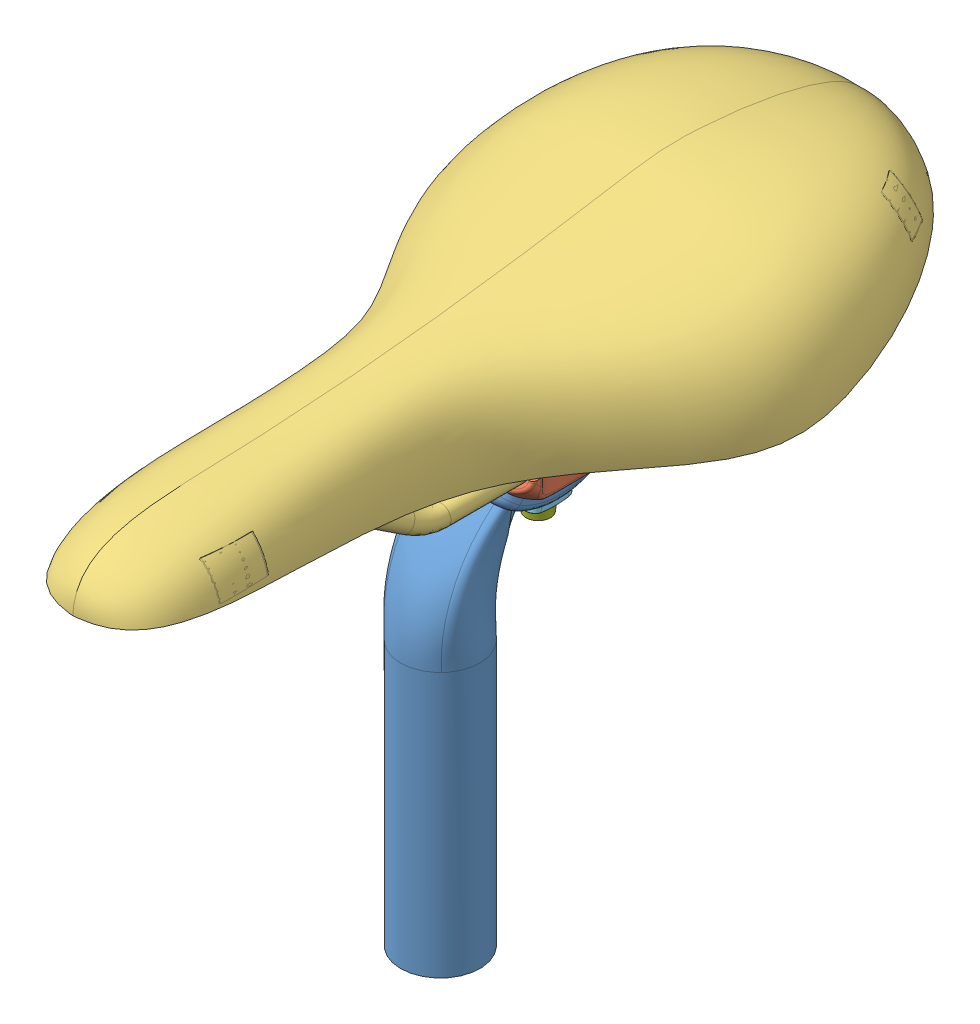
SolidWorks assembly seat_stand, configuration Default. Lengths in mm.
Overall size (140.06 222.45 302.54).
12 component instances, 8 part files, 30 mates.
Components (placement in the parent):
- stand-1: stand [Default] at (5.0908 187.7856 -27.9009) size (40.88 156.43 61.72)
- part_2-1: part_2 [Default] at (5.0908 219.2856 -27.9009) x (0 0 -1) z (1 0 0) size (41.9 15.12 55.13)
- seat_cover-1: seat_cover [Default] at (5.0908 217.7738 -164.6112) x (-1 0 0) z (0 0.049938 -0.998752) size (140.06 58.35 300)
- upper_part_3-1: upper_part_3 [Default] at (5.0908 211.7856 -27.9009) x (0 0 1) z (-1 0 0) size (39.3 9.87 55.04)
- hole_4part-1: hole_4part [Default] at (-6.9092 187.7856 -27.9009) size (12.84 3.36 16.77)
- hole_5part-1: hole_5part [Default] at (-6.9092 218.5862 -27.9009) x (1 0 0) z (0 0 -1) size (12.84 3.15 16.57)
- hole_5part-2: hole_5part [Default] at (17.0908 218.5862 -27.9009) x (1 0 0) z (0 0 -1) size (12.84 3.15 16.57)
- hole_4part-3: hole_4part [Default] at (17.0908 187.7856 -27.9009) size (12.84 3.36 16.77)
- hexalobular socket cheese head_iso-4: hexalobular socket cheese head_iso [ISO 14580 - #6 x 45 x 38 - 4.8-S] at (-6.9092 230.5356 -27.9009) x (1 0 0) z (0 0 -1) size (10 49.4 10)
- hexalobular socket cheese head_iso-5: hexalobular socket cheese head_iso [ISO 14580 - #6 x 45 x 38 - 4.8-S] at (17.0908 230.5356 -27.9009) x (-1 0 0) z (0 0 1) size (10 49.4 10)
- hex flange nut gradea_iso-1: hex flange nut gradea_iso [ISO - 4161 - M6 - N] at (17.0908 226.8362 -27.9009) x (1 0 0) z (0 1 0) size (14.2 14.2 6)
- hex flange nut gradea_iso-2: hex flange nut gradea_iso [ISO - 4161 - M6 - N] at (-6.9092 226.8362 -27.9009) x (1 0 0) z (0 1 0) size (14.2 14.2 6)
Mates (geometry in assembly coordinates):
- Concentric1: concentric anti-aligned: cylinder of stand-1 through (25.0908 219.2856 -27.9009) axis (-1 0 0) radius 24; cylinder of part_2-1 through (5.0908 219.2856 -27.9009) axis (1 0 0) radius 24
- Width1: width aligned: plane of part_2-1 through (25.0908 219.2856 -27.9009) normal (-1 0 0); plane of stand-1 through (-14.9092 219.2856 -27.9009) normal (1 0 0); plane of part_2-1 through (-14.9092 219.2856 -27.9009) normal (-1 0 0); plane of stand-1 through (25.0908 219.2856 -27.9009) normal (1 0 0)
- Parallel1: parallel anti-aligned: plane of stand-1 through (5.0908 45.2856 -2.9009) normal (0 -1 0); plane of part_2-1 through (-22.4392 206.7856 -10.4009) normal (0 1 0)
- Concentric2: concentric anti-aligned: cylinder of part_2-1 through (27.0908 208.2856 -6.9485) axis (0 0 -1) radius 3.65; cylinder of seat_cover-1 through (27.0908 208.2856 -65.927) axis (0 0 1) radius 3.75
- Concentric3: concentric anti-aligned: cylinder of part_2-1 through (-16.9092 208.2856 -6.9485) axis (0 0 -1) radius 3.65; cylinder of seat_cover-1 through (-16.9092 208.2856 -65.927) axis (0 0 1) radius 3.75
- Concentric4: concentric aligned: cylinder of seat_cover-1 through (-16.9092 208.2856 -65.927) axis (0 0 1) radius 3.75; cylinder of upper_part_3-1 through (-16.9092 208.2856 -46.9009) axis (0 0 1) radius 3.75
- Concentric5: concentric aligned: cylinder of seat_cover-1 through (27.0908 208.2856 -65.927) axis (0 0 1) radius 3.75; cylinder of upper_part_3-1 through (27.0908 208.2856 -46.9009) axis (0 0 1) radius 3.75
- Concentric6: concentric anti-aligned: cylinder of part_2-1 through (17.0908 192.3182 -27.9009) axis (0 1 0) radius 4; cylinder of upper_part_3-1 through (17.0908 218.5862 -27.9009) axis (0 -1 0) radius 4
- Concentric7: concentric anti-aligned: cylinder of part_2-1 through (-6.9092 192.3182 -27.9009) axis (0 1 0) radius 4; cylinder of upper_part_3-1 through (-6.9092 218.5862 -27.9009) axis (0 -1 0) radius 4
- Concentric14: concentric aligned: cylinder of stand-1 through (25.0908 219.2856 -27.9009) axis (-1 0 0) radius 31.5; cylinder of hole_4part-1 through (-0.6592 219.2856 -27.9009) axis (-1 0 0) radius 31.5
- Concentric15: concentric aligned: cylinder of part_2-1 through (-6.9092 192.3182 -27.9009) axis (0 1 0) radius 4; cylinder of hole_4part-1 through (-6.9092 185.7856 -27.9009) axis (0 1 0) radius 3.5
- Concentric16: concentric anti-aligned: cylinder of upper_part_3-1 through (-22.4092 178.5862 -27.9009) axis (1 0 0) radius 40; cylinder of hole_5part-1 through (-0.6592 178.5862 -27.9009) axis (-1 0 0) radius 40
- Concentric17: concentric aligned: cylinder of upper_part_3-1 through (-6.9092 218.5862 -27.9009) axis (0 -1 0) radius 4; cylinder of hole_5part-1 through (-6.9092 220.5862 -27.9009) axis (0 -1 0) radius 3.5
- Concentric18: concentric anti-aligned: cylinder of upper_part_3-1 through (-22.4092 178.5862 -27.9009) axis (1 0 0) radius 40; cylinder of hole_5part-2 through (23.3408 178.5862 -27.9009) axis (-1 0 0) radius 40
- Concentric19: concentric aligned: cylinder of upper_part_3-1 through (17.0908 218.5862 -27.9009) axis (0 -1 0) radius 4; cylinder of hole_5part-2 through (17.0908 220.5862 -27.9009) axis (0 -1 0) radius 3.5
- Concentric20: concentric aligned: cylinder of stand-1 through (25.0908 219.2856 -27.9009) axis (-1 0 0) radius 31.5; cylinder of hole_4part-3 through (23.3408 219.2856 -27.9009) axis (-1 0 0) radius 31.5
- Concentric21: concentric aligned: cylinder of part_2-1 through (17.0908 192.3182 -27.9009) axis (0 1 0) radius 4; cylinder of hole_4part-3 through (17.0908 185.7856 -27.9009) axis (0 1 0) radius 3.5
- Concentric22: concentric aligned: cylinder of hole_4part-3 through (17.0908 185.7856 -27.9009) axis (0 1 0) radius 3.5; circle of hexalobular socket cheese head_iso-5
- Concentric23: concentric aligned: cylinder of hole_4part-1 through (-6.9092 185.7856 -27.9009) axis (0 1 0) radius 3.5; circle of hexalobular socket cheese head_iso-4
- Coincident2: coincident anti-aligned: plane of hole_4part-3 through (17.0908 185.5356 -27.9009) normal (0 -1 0); plane of hexalobular socket cheese head_iso-5 through (14.0908 185.5356 -27.9009) normal (0 1 0)
- Coincident3: coincident anti-aligned: plane of hole_4part-1 through (-6.9092 185.5356 -27.9009) normal (0 -1 0); plane of hexalobular socket cheese head_iso-4 through (-3.9092 185.5356 -27.9009) normal (0 1 0)
- Concentric24: concentric anti-aligned: circle of hexalobular socket cheese head_iso-4; circle of hex flange nut gradea_iso-2
- Coincident4: coincident anti-aligned: plane of hole_5part-1 through (-6.9092 220.8362 -27.9009) normal (0 1 0); plane of hex flange nut gradea_iso-2 through (-6.9092 220.8362 -33.6744) normal (0 -1 0)
- Concentric25: concentric anti-aligned: circle of hexalobular socket cheese head_iso-5; circle of hex flange nut gradea_iso-1
- Coincident5: coincident anti-aligned: plane of hole_5part-2 through (17.0908 220.8362 -27.9009) normal (0 1 0); plane of hex flange nut gradea_iso-1 through (17.0908 220.8362 -33.6744) normal (0 -1 0)
- Parallel4: parallel aligned: plane of stand-1 through (5.0908 187.7856 -27.9009) normal (1 0 0); plane of hexalobular socket cheese head_iso-4 through (-6.9092 230.5356 -27.9009) normal (1 0 0)
- Parallel5: parallel anti-aligned: plane of stand-1 through (5.0908 187.7856 -27.9009) normal (1 0 0); plane of hexalobular socket cheese head_iso-5 through (17.0908 230.5356 -27.9009) normal (-1 0 0)
- Parallel7: parallel aligned: plane of hexalobular socket cheese head_iso-4 through (-6.9092 230.5356 -27.9009) normal (1 0 0); plane of hex flange nut gradea_iso-2 through (-6.9092 226.8362 -27.9009) normal (1 0 0)
- Parallel8: parallel anti-aligned: plane of hexalobular socket cheese head_iso-5 through (17.0908 230.5356 -27.9009) normal (-1 0 0); plane of hex flange nut gradea_iso-1 through (17.0908 226.8362 -27.9009) normal (1 0 0)
- Distance1: distance = 105 mm: plane of stand-1 through (5.0908 187.7856 -27.9009) normal (0 0 1); line of seat_cover-1 through (-45.1283 241.2195 -132.9009) axis (1 0 0)
